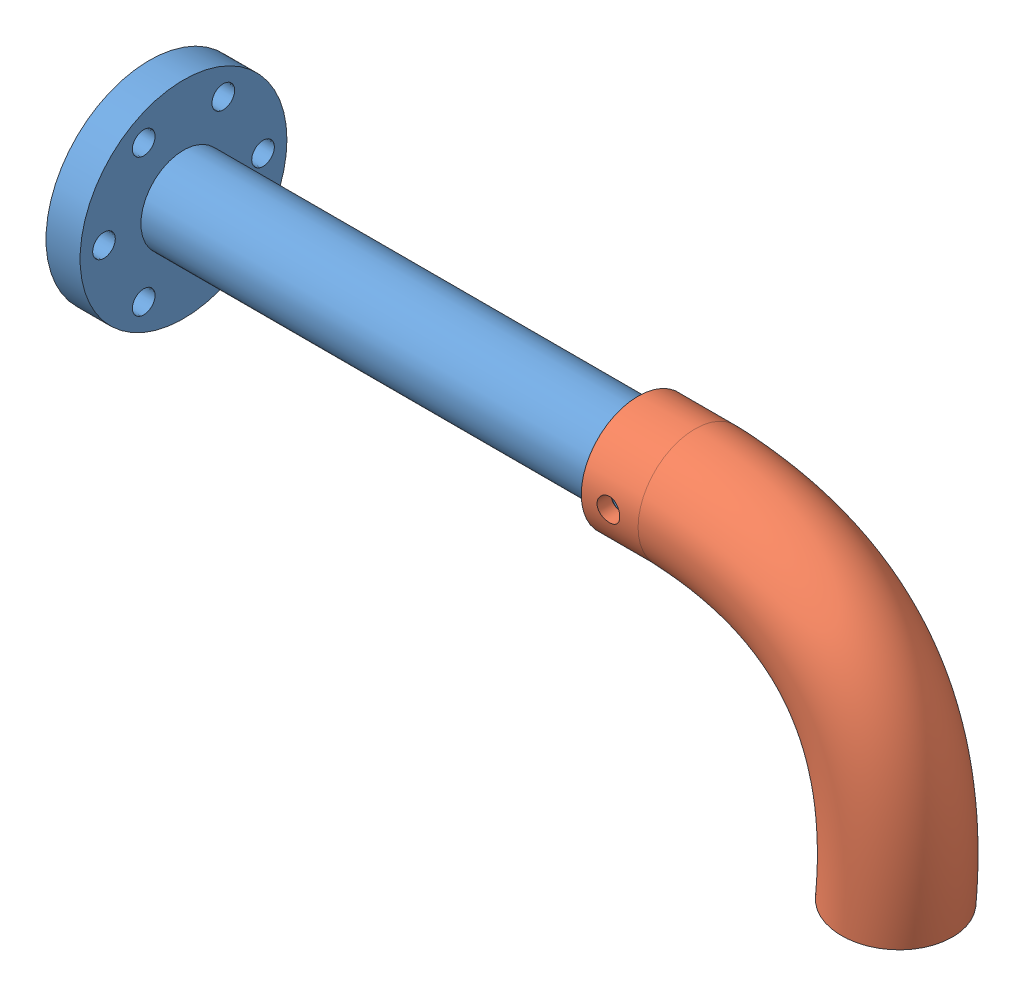
SolidWorks assembly BenchTestAssem, configuration Default. Lengths in mm.
5 component instances, 3 part files, 12 mates.
Components (placement in the parent):
- TestingPaddle-1: TestingPaddle [Default] at (33.9401 55.0956 78.3658) x (0 -1 0) z (0 0 1) size (36.4 96 36.4) (hidden)
- actuator_attach (1)-2: actuator_attach (1) [Default] at (120.9868 109.2347 94.0696) x (0 0 -1) z (-1 0 0) (suppressed, hidden)
- TestingPaddleCurve-2: TestingPaddleCurve [Default] at (129.9401 55.0956 78.3658) x (0 1 0) z (0 0 -1) size (54.8 56.01 20) (hidden)
- 91290A172_BLACK-OXIDE CLASS 12.9 SOCKET HEAD CAP SCREW-2: 91290A172_BLACK-OXIDE CLASS 12.9 SOCKET HEAD CAP SCREW [91290A172] at (124.8152 56.3898 95.8238) (suppressed, hidden)
- locking_mechanism2-1: locking_mechanism2 [Default] at (-70.6771 -140.5742 133.8857) x (0 0 -1) z (1 0 0) (suppressed, hidden)
Mates (geometry in assembly coordinates):
- Coincident2: coincident: plane of TestingPaddle-1 through (119.9401 55.0956 78.3658) normal (1 0 0); plane of TestingPaddleCurve-1 through (119.9401 55.1456 78.3658) normal (-1 0 0)
- Coincident3: coincident: plane of TestingPaddle-1 through (119.9401 60.0956 83.3658) normal (0 0 -1); plane of TestingPaddleCurve-1 through (119.9401 50.1456 83.3658) normal (0 0 1)
- Coincident4: coincident: plane of TestingPaddle-1 through (33.9401 63.0956 78.3658) normal (0 -1 0); line of TestingPaddleCurve-1 through (123.8901 63.0956 73.3658) axis (0 0 1)
- Coincident6: coincident anti-aligned: circle of TestingPaddle-1; circle of TestingPaddleCurve-2
- Concentric1: concentric aligned: circle of actuator_attach (1)-2/202011-ActPack-Geared.STEP-1/AK80-9 3D.STEP-1/AK80-9 3D(2)^AK80-9 3D.STEP-1/AK80-9_ASM_ASM^AK80-9 3D(2)_AK80-9 3D.STEP-1/PRODUCT_46766_ASM_ASM^AK80-9_ASM_ASM_AK80-9 3D(2)_AK80-9 3D.STEP-1/____7^PRODUCT_46766_ASM_ASM_AK80-9_ASM_ASM_AK80-9 3D(2)_AK80-9 3D.STEP-1; circle of MotorHousing_v1-1
- Coincident7: coincident anti-aligned: plane of actuator_attach (1)-2/202011-ActPack-Geared.STEP-1/AK80-9 3D.STEP-1/AK80-9 3D(2)^AK80-9 3D.STEP-1/AK80-9_ASM_ASM^AK80-9 3D(2)_AK80-9 3D.STEP-1/PRODUCT_46766_ASM_ASM^AK80-9_ASM_ASM_AK80-9 3D(2)_AK80-9 3D.STEP-1/____7^PRODUCT_46766_ASM_ASM_AK80-9_ASM_ASM_AK80-9 3D(2)_AK80-9 3D.STEP-1 through (69.9818 33.4468 58.8543) normal (1 0 0); plane of MotorHousing_v1-1 through (69.9818 51.3708 39.2644) normal (-1 0 0)
- Coincident8: coincident anti-aligned: plane of actuator_attach (1)-2/202011-ActPack-Geared.STEP-1/AK80-9 3D.STEP-1/AK80-9 3D(2)^AK80-9 3D.STEP-1/AK80-9_ASM_ASM^AK80-9 3D(2)_AK80-9 3D.STEP-1/PRODUCT_46766_ASM_ASM^AK80-9_ASM_ASM_AK80-9 3D(2)_AK80-9 3D.STEP-1/____7^PRODUCT_46766_ASM_ASM_AK80-9_ASM_ASM_AK80-9 3D(2)_AK80-9 3D.STEP-1 through (69.9818 33.4468 58.8543) normal (1 0 0); plane of MotorHousing_v1-2 through (69.9818 56.0742 58.8425) normal (-1 0 0)
- Concentric2: concentric aligned: circle of actuator_attach (1)-2/202011-ActPack-Geared.STEP-1/AK80-9 3D.STEP-1/AK80-9 3D(2)^AK80-9 3D.STEP-1/AK80-9_ASM_ASM^AK80-9 3D(2)_AK80-9 3D.STEP-1/PRODUCT_46766_ASM_ASM^AK80-9_ASM_ASM_AK80-9 3D(2)_AK80-9 3D.STEP-1/____7^PRODUCT_46766_ASM_ASM_AK80-9_ASM_ASM_AK80-9 3D(2)_AK80-9 3D.STEP-1; circle of MotorHousing_v1-2
- Concentric3: concentric aligned: circle of actuator_attach (1)-2/202011-ActPack-Geared.STEP-1/AK80-9 3D.STEP-1/AK80-9 3D(2)^AK80-9 3D.STEP-1/AK80-9_ASM_ASM^AK80-9 3D(2)_AK80-9 3D.STEP-1/PRODUCT_46766_ASM_ASM^AK80-9_ASM_ASM_AK80-9 3D(2)_AK80-9 3D.STEP-1/____5^PRODUCT_46766_ASM_ASM_AK80-9_ASM_ASM_AK80-9 3D(2)_AK80-9 3D.STEP-1; circle of RotorAttach_v1-1
- Coincident9: coincident anti-aligned: plane of actuator_attach (1)-2/202011-ActPack-Geared.STEP-1/AK80-9 3D.STEP-1/AK80-9 3D(2)^AK80-9 3D.STEP-1/AK80-9_ASM_ASM^AK80-9 3D(2)_AK80-9 3D.STEP-1/PRODUCT_46766_ASM_ASM^AK80-9_ASM_ASM_AK80-9 3D(2)_AK80-9 3D.STEP-1/____7^PRODUCT_46766_ASM_ASM_AK80-9_ASM_ASM_AK80-9 3D(2)_AK80-9 3D.STEP-1 through (69.9818 33.4468 58.8543) normal (1 0 0); plane of MotorHousing_v1-3 through (69.9818 57.3617 59.0613) normal (-1 0 0)
- Concentric4: concentric aligned: circle of actuator_attach (1)-2/202011-ActPack-Geared.STEP-1/AK80-9 3D.STEP-1/AK80-9 3D(2)^AK80-9 3D.STEP-1/AK80-9_ASM_ASM^AK80-9 3D(2)_AK80-9 3D.STEP-1/PRODUCT_46766_ASM_ASM^AK80-9_ASM_ASM_AK80-9 3D(2)_AK80-9 3D.STEP-1/____7^PRODUCT_46766_ASM_ASM_AK80-9_ASM_ASM_AK80-9 3D(2)_AK80-9 3D.STEP-1; circle of MotorHousing_v1-3
- Concentric5: concentric aligned: circle of RotorAttach_v1-1; circle of locking_mechanism2-1/lock2_hinged-1
